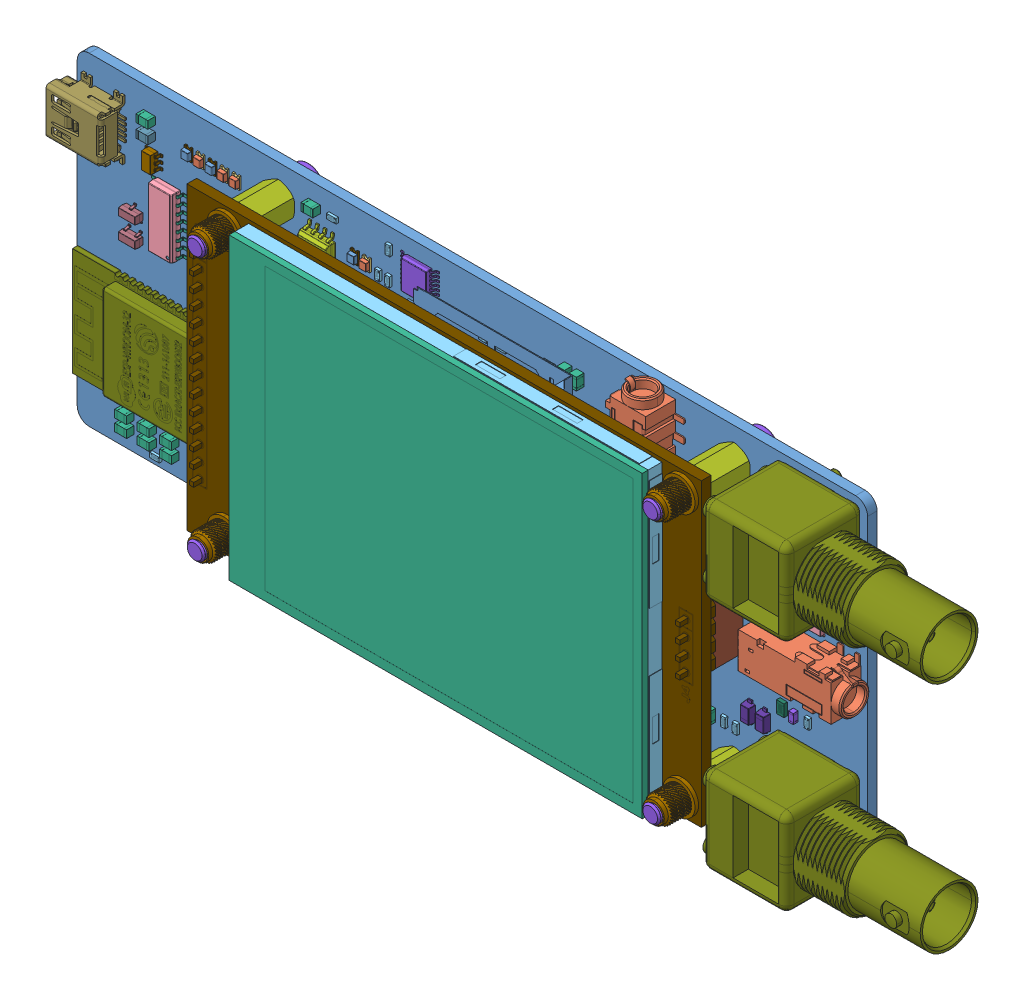
SolidWorks assembly TIK_PCB_20220619, configuration Default. Lengths in mm.
Overall size (153.42 59.57 22.01).
334 component instances, 49 part files, 0 mates.
Components (placement in the parent):
- TIK_PCB_20220619.step-1: TIK_PCB_20220619.step [Default] at origin size (153.42 59.57 22.01)
  - BoardTIK_PCB.step-1: BoardTIK_PCB.step [Default] at origin size (127 56 1.59)
    - Open CASCADE STEP translator 6.8 2.1.1.step-1: Open CASCADE STEP translator 6.8 2.1.1.step [Predeterminado] at (0 0 -1.59) size (127 56 1.59)
  - J6TIK_PCB.step-1: J6TIK_PCB.step [Default] at origin size (9 19.2 5.8)
    - CUI_DEVICES_SJ-43516-SMT-TR.step-1: CUI_DEVICES_SJ-43516-SMT-TR.step [Default] at (173.0501 135.9999 2.6) x (0 1 0) z (1 0 0) size (19.2 5.8 9)
  - U6TIK_PCB.step-1: U6TIK_PCB.step [Default] at origin size (4.9 3 1.1)
    - TI_VSSOP-8_DGK.step-1: TI_VSSOP-8_DGK.step [Default] at (178.0502 98.5 0) x (0 1 0) z (1 0 0) size (3 1.1 4.9)
  - U11TIK_PCB.step-1: U11TIK_PCB.step [Default] at origin size (2.9 2.8 1.1)
    - TI_-_TSOT-23-6_v2.step-1: TI_-_TSOT-23-6_v2.step [Default] at (199.75 115.5 0) x (0 -1 0) z (0 0 1) size (2.8 2.9 1.1)
  - R40TIK_PCB.step-1: R40TIK_PCB.step [Default] at origin size (0.8 1.6 0.45)
    - 0603_resistor.step-1: 0603_resistor.step [Default] at (177.1 122.3499 0) x (0 1 0) z (1 0 0) size (1.6 0.45 0.8)
  - R39TIK_PCB.step-1: R39TIK_PCB.step [Default] at origin size (1.6 0.8 0.45)
    - 0603_resistor.step-1: 0603_resistor.step [Default] at (189.4718 119.0829 0) x (1 0 0) z (0 -1 0) size (1.6 0.45 0.8)
  - C43TIK_PCB.step-1: C43TIK_PCB.step [Default] at origin size (1.27 2 1.27)
    - 0805_cap.step-1: 0805_cap.step [Default] at (196.363 115.3001 0.62) x (0 -1 0) z (0 0 1) size (2 1.27 1.27)
  - C42TIK_PCB.step-1: C42TIK_PCB.step [Default] at origin size (1.27 2 1.27)
    - 0805_cap.step-1: 0805_cap.step [Default] at (176.863 125.8001 0.62) x (0 -1 0) z (0 0 1) size (2 1.27 1.27)
  - C41TIK_PCB.step-1: C41TIK_PCB.step [Default] at origin size (2 1.27 1.27)
    - 0805_cap.step-1: 0805_cap.step [Default] at (189.1218 116.0459 0.62) x (1 0 0) z (0 0 1) size (2 1.27 1.27)
  - R20TIK_PCB.step-1: R20TIK_PCB.step [Default] at origin size (1.6 3.2 0.6)
    - 1206_resistor.step-1: 1206_resistor.step [Default] at (121.5499 105.1 0) x (0 -1 0) z (-1 0 0) size (3.2 0.6 1.6)
  - J5TIK_PCB.step-1: J5TIK_PCB.step [Default] at origin size (19.2 9 5.8)
    - CUI_DEVICES_SJ-43516-SMT-TR.step-1: CUI_DEVICES_SJ-43516-SMT-TR.step [Default] at (206.9999 109.9499 2.6) x (1 0 0) z (0 -1 0) size (19.2 5.8 9)
  - C25TIK_PCB.step-1: C25TIK_PCB.step [Default] at origin size (0.82 1.6 0.82)
    - 0603_cap.step-1: 0603_cap.step [Default] at (171.7501 98.5749 0) x (0 -1 0) z (-1 0 0) size (1.6 0.82 0.82)
  - R8TIK_PCB.step-1: R8TIK_PCB.step [Default] at origin size (1.6 0.8 0.45)
    - 0603_resistor.step-1: 0603_resistor.step [Default] at (118.8499 134.1 0) x (1 0 0) z (0 -1 0) size (1.6 0.45 0.8)
  - R2TIK_PCB.step-1: R2TIK_PCB.step [Default] at origin size (0.8 1.6 0.45)
    - 0603_resistor.step-1: 0603_resistor.step [Default] at (105.4 129.6501 0) x (0 -1 0) z (-1 0 0) size (1.6 0.45 0.8)
  - C33TIK_PCB.step-1: C33TIK_PCB.step [Default] at origin size (2 1.27 1.27)
    - 0805_cap.step-1: 0805_cap.step [Default] at (199.7501 119.387 0.62) x (-1 0 0) z (0 0 1) size (2 1.27 1.27)
  - C24TIK_PCB.step-1: C24TIK_PCB.step [Default] at origin size (1.6 3.2 1)
    - CAP_1206-1mm.step-1: CAP_1206-1mm.step [Default] at (191.0001 128.0499 0) x (0 -1 0) z (-1 0 0) size (3.2 1 1.6)
  - C23TIK_PCB.step-1: C23TIK_PCB.step [Default] at origin size (1.6 3.2 1)
    - CAP_1206-1mm.step-1: CAP_1206-1mm.step [Default] at (190.9999 91.9501 0) x (0 1 0) z (1 0 0) size (3.2 1 1.6)
  - U10TIK_PCB.step-1: U10TIK_PCB.step [Default] at origin size (10.01 6 1.75)
    - 6371753328.step-1: 6371753328.step [Default] at (149.545 124.325 0) x (0 1 0) z (0 0 1) size (6 10.01 1.75)
      - Body.step-1: Body.step [Default] at (-2 -5 0) size (4 10.01 1.65)
        - Open_CASCADE_STEP_translator_6.8_6.2.1.step-1: Open_CASCADE_STEP_translator_6.8_6.2.1.step [Default] at origin size (4 10.01 1.65)
      - Open_CASCADE_STEP_translator_6.8_6.1.step-1: Open_CASCADE_STEP_translator_6.8_6.1.step [Default] at (-2 -5 0.001) size (0.5 0.5 0)
      - Leader.step-1: Leader.step [Default] at (-2 -4.445 0) x (-1 0 0) z (0 0 1) size (1 0.41 0.97)
      - Leader.step-2: Leader.step [Default] at (-2 -3.175 0) x (-1 0 0) z (0 0 1) size (1 0.41 0.97)
      - Leader.step-3: Leader.step [Default] at (-2 -1.905 0) x (-1 0 0) z (0 0 1) size (1 0.41 0.97)
      - Leader.step-4: Leader.step [Default] at (-2 -0.635 0) x (-1 0 0) z (0 0 1) size (1 0.41 0.97)
      - Leader.step-5: Leader.step [Default] at (-2 0.635 0) x (-1 0 0) z (0 0 1) size (1 0.41 0.97)
      - Leader.step-6: Leader.step [Default] at (-2 1.905 0) x (-1 0 0) z (0 0 1) size (1 0.41 0.97)
      - Leader.step-7: Leader.step [Default] at (-2 3.175 0) x (-1 0 0) z (0 0 1) size (1 0.41 0.97)
      - Leader.step-8: Leader.step [Default] at (-2 4.445 0) x (-1 0 0) z (0 0 1) size (1 0.41 0.97)
      - Leader.step-9: Leader.step [Default] at (2 -4.445 0) size (1 0.41 0.97)
      - Leader.step-10: Leader.step [Default] at (2 -3.175 0) size (1 0.41 0.97)
      - Leader.step-11: Leader.step [Default] at (2 -1.905 0) size (1 0.41 0.97)
      - Leader.step-12: Leader.step [Default] at (2 -0.635 0) size (1 0.41 0.97)
      - Leader.step-13: Leader.step [Default] at (2 0.635 0) size (1 0.41 0.97)
      - Leader.step-14: Leader.step [Default] at (2 1.905 0) size (1 0.41 0.97)
      - Leader.step-15: Leader.step [Default] at (2 3.175 0) size (1 0.41 0.97)
      - Leader.step-16: Leader.step [Default] at (2 4.445 0) size (1 0.41 0.97)
  - R34TIK_PCB.step-1: R34TIK_PCB.step [Default] at origin size (0.8 1.6 0.45)
    - 0603_resistor.step-1: 0603_resistor.step [Default] at (156.1 119.3499 0) x (0 1 0) z (1 0 0) size (1.6 0.45 0.8)
  - R33TIK_PCB.step-1: R33TIK_PCB.step [Default] at origin size (0.8 1.6 0.45)
    - 0603_resistor.step-1: 0603_resistor.step [Default] at (156.9 126.1001 0) x (0 -1 0) z (-1 0 0) size (1.6 0.45 0.8)
  - R38TIK_PCB.step-1: R38TIK_PCB.step [Default] at origin size (1.6 0.8 0.45)
    - 0603_resistor.step-1: 0603_resistor.step [Default] at (150.5001 118.85 0) x (-1 0 0) z (0 1 0) size (1.6 0.45 0.8)
  - R37TIK_PCB.step-1: R37TIK_PCB.step [Default] at origin size (1.6 0.8 0.45)
    - 0603_resistor.step-1: 0603_resistor.step [Default] at (147.1501 128.65 0) x (-1 0 0) z (0 1 0) size (1.6 0.45 0.8)
  - R36TIK_PCB.step-1: R36TIK_PCB.step [Default] at origin size (1.6 0.8 0.45)
    - 0603_resistor.step-1: 0603_resistor.step [Default] at (147.5001 118.85 0) x (-1 0 0) z (0 1 0) size (1.6 0.45 0.8)
  - R35TIK_PCB.step-1: R35TIK_PCB.step [Default] at origin size (1.6 0.8 0.45)
    - 0603_resistor.step-1: 0603_resistor.step [Default] at (144.2501 128.6 0) x (-1 0 0) z (0 1 0) size (1.6 0.45 0.8)
  - Q6TIK_PCB.step-1: Q6TIK_PCB.step [Default] at origin size (2.9 2.32 1.5)
    - sot-23-3-nxp.step-1: sot-23-3-nxp.step [Default] at (142.25 119.2501 0) x (-1 0 0) z (0 1 0) size (2.9 1.5 2.32)
  - FB2TIK_PCB.step-1: FB2TIK_PCB.step [Default] at origin size (2 1.27 1.27)
    - FER_0805.step-1: FER_0805.step [Default] at (154.9501 130.887 0.62) x (-1 0 0) z (0 0 1) size (2 1.27 1.27)
  - C36TIK_PCB.step-1: C36TIK_PCB.step [Default] at origin size (1.27 2 1.27)
    - 0805_cap.step-1: 0805_cap.step [Default] at (143.837 126.2499 0.62) x (0 1 0) z (0 0 1) size (2 1.27 1.27)
  - C35TIK_PCB.step-1: C35TIK_PCB.step [Default] at origin size (1.27 2 1.27)
    - 0805_cap.step-1: 0805_cap.step [Default] at (141.837 126.2499 0.62) x (0 1 0) z (0 0 1) size (2 1.27 1.27)
  - C34TIK_PCB.step-1: C34TIK_PCB.step [Default] at origin size (1.27 2 1.27)
    - 0805_cap.step-1: 0805_cap.step [Default] at (139.837 126.2499 0.62) x (0 1 0) z (0 0 1) size (2 1.27 1.27)
  - C39TIK_PCB.step-1: C39TIK_PCB.step [Default] at origin size (1.27 2 1.27)
    - 0805_cap.step-1: 0805_cap.step [Default] at (157.137 122.6999 0.62) x (0 1 0) z (0 0 1) size (2 1.27 1.27)
  - C40TIK_PCB.step-1: C40TIK_PCB.step [Default] at origin size (2 1.27 1.27)
    - 0805_cap.step-1: 0805_cap.step [Default] at (153.8001 119.637 0.62) x (-1 0 0) z (0 0 1) size (2 1.27 1.27)
  - C38TIK_PCB.step-1: C38TIK_PCB.step [Default] at origin size (1.27 2 1.27)
    - 0805_cap.step-1: 0805_cap.step [Default] at (157.3629 131.0501 0.62) x (0 -1 0) z (0 0 1) size (2 1.27 1.27)
  - C37TIK_PCB.step-1: C37TIK_PCB.step [Default] at origin size (1.27 2 1.27)
    - 0805_cap.step-1: 0805_cap.step [Default] at (159.363 131.0501 0.62) x (0 -1 0) z (0 0 1) size (2 1.27 1.27)
  - R11TIK_PCB.step-1: R11TIK_PCB.step [Default] at origin size (1.6 0.8 0.45)
    - 0603_resistor.step-1: 0603_resistor.step [Default] at (144.7501 90.6 0) x (-1 0 0) z (0 1 0) size (1.6 0.45 0.8)
  - C26TIK_PCB.step-1: C26TIK_PCB.step [Default] at origin size (1.27 2 1.27)
    - 0805_cap.step-1: 0805_cap.step [Default] at (169.113 98.2001 0.62) x (0 -1 0) z (0 0 1) size (2 1.27 1.27)
  - R17TIK_PCB.step-1: R17TIK_PCB.step [Default] at origin size (1.25 2 0.6)
    - 0805_resistor.step-1: 0805_resistor.step [Default] at (174.375 98.625 0) x (0 -1 0) z (-1 0 0) size (2 0.6 1.25)
  - R16TIK_PCB.step-1: R16TIK_PCB.step [Default] at origin size (0.8 1.6 0.45)
    - 0603_resistor.step-1: 0603_resistor.step [Default] at (186.65 123.6001 0) x (0 -1 0) z (-1 0 0) size (1.6 0.45 0.8)
  - R15TIK_PCB.step-1: R15TIK_PCB.step [Default] at origin size (0.8 1.6 0.45)
    - 0603_resistor.step-1: 0603_resistor.step [Default] at (197.85 100.3749 0) x (0 1 0) z (1 0 0) size (1.6 0.45 0.8)
  - R14TIK_PCB.step-1: R14TIK_PCB.step [Default] at origin size (1.25 2 0.6)
    - 0805_resistor.step-1: 0805_resistor.step [Default] at (194.625 100.475 0) x (0 -1 0) z (-1 0 0) size (2 0.6 1.25)
  - J3TIK_PCB.step-1: J3TIK_PCB.step [Default] at origin size (35.41 14.41 17.87)
    - 31-71043_1.step-1: 31-71043_1.step [Default] at (202.8647 129.4999 6.6) x (1 0 0) z (0 -1 0) size (35.41 17.87 14.41)
  - J2TIK_PCB.step-1: J2TIK_PCB.step [Default] at origin size (35.41 14.41 17.87)
    - 31-71043_1.step-1: 31-71043_1.step [Default] at (202.8647 90.4999 6.6) x (1 0 0) z (0 -1 0) size (35.41 17.87 14.41)
  - D5TIK_PCB.step-1: D5TIK_PCB.step [Default] at origin size (1.6 3.5 1.1)
    - SOD123F.step-1: SOD123F.step [Default] at (191.0001 122.8199 0) x (0 -1 0) z (-1 0 0) size (3.5 1.1 1.6)
  - D4TIK_PCB.step-1: D4TIK_PCB.step [Default] at origin size (1.6 3.5 1.1)
    - SOD123F.step-1: SOD123F.step [Default] at (188.4999 122.8201 0) x (0 1 0) z (1 0 0) size (3.5 1.1 1.6)
  - D3TIK_PCB.step-1: D3TIK_PCB.step [Default] at origin size (1.6 3.5 1.1)
    - SOD123F.step-1: SOD123F.step [Default] at (190.9999 97.0701 0) x (0 1 0) z (1 0 0) size (3.5 1.1 1.6)
  - D2TIK_PCB.step-1: D2TIK_PCB.step [Default] at origin size (1.6 3.5 1.1)
    - SOD123F.step-1: SOD123F.step [Default] at (188.5001 97.0699 0) x (0 -1 0) z (-1 0 0) size (3.5 1.1 1.6)
  - C27TIK_PCB.step-1: C27TIK_PCB.step [Default] at origin size (1.27 2 1.27)
    - 0805_cap.step-1: 0805_cap.step [Default] at (166.863 98.2001 0.62) x (0 -1 0) z (0 0 1) size (2 1.27 1.27)
  - C22TIK_PCB.step-1: C22TIK_PCB.step [Default] at origin size (0.82 1.6 0.82)
    - 0603_cap.step-1: 0603_cap.step [Default] at (196.0001 100.2749 0) x (0 -1 0) z (-1 0 0) size (1.6 0.82 0.82)
  - R29TIK_PCB.step-1: R29TIK_PCB.step [Default] at origin size (0.8 1.6 0.45)
    - 0603_resistor.step-1: 0603_resistor.step [Default] at (100.4 124.1001 0) x (0 -1 0) z (-1 0 0) size (1.6 0.45 0.8)
  - D11TIK_PCB.step-1: D11TIK_PCB.step [Default] at origin size (1.25 2 0.9)
    - LED_0805_Base_RED.step-1: LED_0805_Base_RED.step [Default] at (98.75 130.9501 0) x (0 1 0) z (1 0 0) size (2 0.4 1.25)
    - LED_0805_Lens_RED.step-1: LED_0805_Lens_RED.step [Default] at (98.75 130.9501 0) x (0 1 0) z (1 0 0) size (1.3 0.6 1.25)
  - D10TIK_PCB.step-1: D10TIK_PCB.step [Default] at origin size (1.25 2 0.9)
    - LED_0805_Lens_GREEN.step-1: LED_0805_Lens_GREEN.step [Default] at (100.75 130.9501 0) x (0 1 0) z (1 0 0) size (1.3 0.6 1.25)
    - LED_0805_Base_GREEN.step-1: LED_0805_Base_GREEN.step [Default] at (100.75 130.9501 0) x (0 1 0) z (1 0 0) size (2 0.4 1.25)
  - D9TIK_PCB.step-1: D9TIK_PCB.step [Default] at origin size (1.25 2 0.9)
    - LED_0805_Lens_RED.step-1: LED_0805_Lens_RED.step [Default] at (94.75 130.9501 0) x (0 1 0) z (1 0 0) size (1.3 0.6 1.25)
    - LED_0805_Base_RED.step-1: LED_0805_Base_RED.step [Default] at (94.75 130.9501 0) x (0 1 0) z (1 0 0) size (2 0.4 1.25)
  - D1TIK_PCB.step-1: D1TIK_PCB.step [Default] at origin size (1.25 2 0.9)
    - LED_0805_Base_GREEN.step-1: LED_0805_Base_GREEN.step [Default] at (102.75 130.9501 0) x (0 1 0) z (1 0 0) size (2 0.4 1.25)
    - LED_0805_Lens_GREEN.step-1: LED_0805_Lens_GREEN.step [Default] at (102.75 130.9501 0) x (0 1 0) z (1 0 0) size (1.3 0.6 1.25)
  - D6TIK_PCB.step-1: D6TIK_PCB.step [Default] at origin size (1.25 2 0.9)
    - LED_0805_Lens_GREEN.step-1: LED_0805_Lens_GREEN.step [Default] at (124.5 129.8999 0) x (0 -1 0) z (-1 0 0) size (1.3 0.6 1.25)
    - LED_0805_Base_GREEN.step-1: LED_0805_Base_GREEN.step [Default] at (124.5 129.8999 0) x (0 -1 0) z (-1 0 0) size (2 0.4 1.25)
  - D7TIK_PCB.step-1: D7TIK_PCB.step [Default] at origin size (1.25 2 0.9)
    - LED_0805_Base_RED.step-1: LED_0805_Base_RED.step [Default] at (122.5 129.8999 0) x (0 -1 0) z (-1 0 0) size (2 0.4 1.25)
    - LED_0805_Lens_RED.step-1: LED_0805_Lens_RED.step [Default] at (122.5 129.8999 0) x (0 -1 0) z (-1 0 0) size (1.3 0.6 1.25)
  - D8TIK_PCB.step-1: D8TIK_PCB.step [Default] at origin size (1.25 2 0.9)
    - LED_0805_Base_GREEN.step-1: LED_0805_Base_GREEN.step [Default] at (96.75 130.9501 0) x (0 1 0) z (1 0 0) size (2 0.4 1.25)
    - LED_0805_Lens_GREEN.step-1: LED_0805_Lens_GREEN.step [Default] at (96.75 130.9501 0) x (0 1 0) z (1 0 0) size (1.3 0.6 1.25)
  - R24TIK_PCB.step-1: R24TIK_PCB.step [Default] at origin size (0.8 1.6 0.45)
    - 0603_resistor.step-1: 0603_resistor.step [Default] at (128.6 129.3501 0) x (0 -1 0) z (-1 0 0) size (1.6 0.45 0.8)
  - C29TIK_PCB.step-1: C29TIK_PCB.step [Default] at origin size (2 1.27 1.27)
    - 0805_cap.step-1: 0805_cap.step [Default] at (116.5501 118.387 0.62) x (-1 0 0) z (0 0 1) size (2 1.27 1.27)
  - U9TIK_PCB.step-1: U9TIK_PCB.step [Default] at origin size (6 10.01 1.75)
    - 6371753168.step-1: 6371753168.step [Default] at (91.5 120 0) x (-1 0 0) z (0 0 1) size (6 10.01 1.75)
      - Body-1.step-1: Body-1.step [Default] at (-2 -5 0) size (4 10.01 1.65)
        - Open_CASCADE_STEP_translator_6.8_6.2.1-0.step-1: Open_CASCADE_STEP_translator_6.8_6.2.1-0.step [Default] at origin size (4 10.01 1.65)
      - Open_CASCADE_STEP_translator_6.8_6.1-1.step-1: Open_CASCADE_STEP_translator_6.8_6.1-1.step [Default] at (-2 -5 0.001) size (0.5 0.5 0)
      - Leader-2.step-1: Leader-2.step [Default] at (-2 -4.445 0) x (-1 0 0) z (0 0 1) size (1 0.41 0.97)
      - Leader-2.step-2: Leader-2.step [Default] at (-2 -3.175 0) x (-1 0 0) z (0 0 1) size (1 0.41 0.97)
      - Leader-2.step-3: Leader-2.step [Default] at (-2 -1.905 0) x (-1 0 0) z (0 0 1) size (1 0.41 0.97)
      - Leader-2.step-4: Leader-2.step [Default] at (-2 -0.635 0) x (-1 0 0) z (0 0 1) size (1 0.41 0.97)
      - Leader-2.step-5: Leader-2.step [Default] at (-2 0.635 0) x (-1 0 0) z (0 0 1) size (1 0.41 0.97)
      - Leader-2.step-6: Leader-2.step [Default] at (-2 1.905 0) x (-1 0 0) z (0 0 1) size (1 0.41 0.97)
      - Leader-2.step-7: Leader-2.step [Default] at (-2 3.175 0) x (-1 0 0) z (0 0 1) size (1 0.41 0.97)
      - Leader-2.step-8: Leader-2.step [Default] at (-2 4.445 0) x (-1 0 0) z (0 0 1) size (1 0.41 0.97)
      - Leader-2.step-9: Leader-2.step [Default] at (2 -4.445 0) size (1 0.41 0.97)
      - Leader-2.step-10: Leader-2.step [Default] at (2 -3.175 0) size (1 0.41 0.97)
      - Leader-2.step-11: Leader-2.step [Default] at (2 -1.905 0) size (1 0.41 0.97)
      - Leader-2.step-12: Leader-2.step [Default] at (2 -0.635 0) size (1 0.41 0.97)
      - Leader-2.step-13: Leader-2.step [Default] at (2 0.635 0) size (1 0.41 0.97)
      - Leader-2.step-14: Leader-2.step [Default] at (2 1.905 0) size (1 0.41 0.97)
      - Leader-2.step-15: Leader-2.step [Default] at (2 3.175 0) size (1 0.41 0.97)
      - Leader-2.step-16: Leader-2.step [Default] at (2 4.445 0) size (1 0.41 0.97)
  - U8TIK_PCB.step-1: U8TIK_PCB.step [Default] at origin size (4.91 6 1.75)
    - TI_-_SOIC-8_-_D008A_v3.step-1: TI_-_SOIC-8_-_D008A_v3.step [Default] at (116.635 104.1 0) x (0 -1 0) z (0 0 1) size (6 4.9 1.75)
  - U7TIK_PCB.step-1: U7TIK_PCB.step [Default] at origin size (6.4 5 1.2)
    - TI_-_SOP-16_-_PWP0016C_v2.step-1: TI_-_SOP-16_-_PWP0016C_v2.step [Default] at (133.35 132.225 0) x (-1 0 0) z (0 0 1) size (6.4 5 1.2)
      - Component4.step-1: Component4.step [Default] at origin size (6.4 5 1.2)
  - U4TIK_PCB.step-1: U4TIK_PCB.step [Default] at origin size (4.91 6 1.75)
    - TI_-_SOIC-8_-_D008A_v3.step-1: TI_-_SOIC-8_-_D008A_v3.step [Default] at (116.885 128.5 0) x (0 1 0) z (0 0 1) size (6 4.9 1.75)
  - U3TIK_PCB.step-1: U3TIK_PCB.step [Default] at origin size (2.82 2.9 1.45)
    - sot-23-6-atmel.step-1: sot-23-6-atmel.step [Default] at (117.875 122.5499 0) x (0 -1 0) z (-1 0 0) size (2.9 1.45 2.82)
  - U2TIK_PCB.step-1: U2TIK_PCB.step [Default] at origin size (1.85 2 1.1)
    - sc_82ab.step-1: sc_82ab.step [Default] at (173.7746 94.1652 0) x (0 -1 0) z (0 0 -1) size (2 1.85 1.1)
  - U1TIK_PCB.step-1: U1TIK_PCB.step [Default] at origin size (3.1 3 1.45)
    - DIODES_INC_-_SOT-23-5_-_N.step-1: DIODES_INC_-_SOT-23-5_-_N.step [Default] at (126.5 105.2501 0) x (0 1 0) z (0 0 1) size (3 3.1 1.45)
  - S4TIK_PCB.step-1: S4TIK_PCB.step [Default] at origin size (8 3.61 2.52)
    - Tactile_Switch_SMD_6x3.6mm_H=2.5mm_RS-282G05A3-SM_RT.step-1: Tactile_Switch_SMD_6x3.6mm_H=2.5mm_RS-282G05A3-SM_RT.step [Default] at (99.1232 87.0004 0) x (-1 0 0) z (0 0 1) size (8 3.6 2.52)
  - S1TIK_PCB.step-1: S1TIK_PCB.step [Default] at origin size (17.45 11.87 3.02)
    - SLLB510100_SCALED_CROP.step-1: SLLB510100_SCALED_CROP.step [Default] at (150.023 87.4461 7.7) x (1 0 0) z (0 0 1) size (17.45 11.87 3.02)
  - S3TIK_PCB.step-1: S3TIK_PCB.step [Default] at origin size (8 3.61 2.52)
    - Tactile_Switch_SMD_6x3.6mm_H=2.5mm_RS-282G05A3-SM_RT.step-1: Tactile_Switch_SMD_6x3.6mm_H=2.5mm_RS-282G05A3-SM_RT.step [Default] at (164.0163 87.0004 0) x (-1 0 0) z (0 0 1) size (8 3.6 2.52)
  - S2TIK_PCB.step-1: S2TIK_PCB.step [Default] at origin size (8 3.61 2.52)
    - Tactile_Switch_SMD_6x3.6mm_H=2.5mm_RS-282G05A3-SM_RT.step-1: Tactile_Switch_SMD_6x3.6mm_H=2.5mm_RS-282G05A3-SM_RT.step [Default] at (177.5163 87.0004 0) x (-1 0 0) z (0 0 1) size (8 3.6 2.52)
  - R32TIK_PCB.step-1: R32TIK_PCB.step [Default] at origin size (1.6 0.8 0.45)
    - 0603_resistor.step-1: 0603_resistor.step [Default] at (115.6399 86.65 0) x (1 0 0) z (0 -1 0) size (1.6 0.45 0.8)
  - R31TIK_PCB.step-1: R31TIK_PCB.step [Default] at origin size (1.6 0.8 0.45)
    - 0603_resistor.step-1: 0603_resistor.step [Default] at (115.6399 88.4 0) x (1 0 0) z (0 -1 0) size (1.6 0.45 0.8)
  - R30TIK_PCB.step-1: R30TIK_PCB.step [Default] at origin size (1.6 0.8 0.45)
    - 0603_resistor.step-1: 0603_resistor.step [Default] at (118.3499 98.3 0) x (1 0 0) z (0 -1 0) size (1.6 0.45 0.8)
  - R28TIK_PCB.step-1: R28TIK_PCB.step [Default] at origin size (0.8 1.6 0.45)
    - 0603_resistor.step-1: 0603_resistor.step [Default] at (102.15 124.1001 0) x (0 -1 0) z (-1 0 0) size (1.6 0.45 0.8)
  - R27TIK_PCB.step-1: R27TIK_PCB.step [Default] at origin size (0.8 1.6 0.45)
    - 0603_resistor.step-1: 0603_resistor.step [Default] at (96.9 124.1001 0) x (0 -1 0) z (-1 0 0) size (1.6 0.45 0.8)
  - R19TIK_PCB.step-1: R19TIK_PCB.step [Default] at origin size (1.6 0.8 0.45)
    - 0603_resistor.step-1: 0603_resistor.step [Default] at (133.9499 129 0) x (1 0 0) z (0 -1 0) size (1.6 0.45 0.8)
  - R18TIK_PCB.step-1: R18TIK_PCB.step [Default] at origin size (0.8 1.6 0.45)
    - 0603_resistor.step-1: 0603_resistor.step [Default] at (128.65 133.8501 0) x (0 -1 0) z (-1 0 0) size (1.6 0.45 0.8)
  - R25TIK_PCB.step-1: R25TIK_PCB.step [Default] at origin size (0.8 1.6 0.45)
    - 0603_resistor.step-1: 0603_resistor.step [Default] at (123 114.5499 0) x (0 1 0) z (1 0 0) size (1.6 0.45 0.8)
  - R26TIK_PCB.step-1: R26TIK_PCB.step [Default] at origin size (0.8 1.6 0.45)
    - 0603_resistor.step-1: 0603_resistor.step [Default] at (98.65 124.1001 0) x (0 -1 0) z (-1 0 0) size (1.6 0.45 0.8)
  - R13TIK_PCB.step-1: R13TIK_PCB.step [Default] at origin size (1.6 0.8 0.45)
    - 0603_resistor.step-1: 0603_resistor.step [Default] at (162.2501 89.6 0) x (-1 0 0) z (0 1 0) size (1.6 0.45 0.8)
  - R12TIK_PCB.step-1: R12TIK_PCB.step [Default] at origin size (1.6 0.8 0.45)
    - 0603_resistor.step-1: 0603_resistor.step [Default] at (89.3501 84 0) x (-1 0 0) z (0 1 0) size (1.6 0.45 0.8)
  - R10TIK_PCB.step-1: R10TIK_PCB.step [Default] at origin size (1.6 0.8 0.45)
    - 0603_resistor.step-1: 0603_resistor.step [Default] at (157.9999 91.4 0) x (1 0 0) z (0 -1 0) size (1.6 0.45 0.8)
  - R9TIK_PCB.step-1: R9TIK_PCB.step [Default] at origin size (1.6 0.8 0.45)
    - 0603_resistor.step-1: 0603_resistor.step [Default] at (155.1499 91.4 0) x (1 0 0) z (0 -1 0) size (1.6 0.45 0.8)
  - R23TIK_PCB.step-1: R23TIK_PCB.step [Default] at origin size (0.8 1.6 0.45)
    - 0603_resistor.step-1: 0603_resistor.step [Default] at (126.9 129.3501 0) x (0 -1 0) z (-1 0 0) size (1.6 0.45 0.8)
  - R7TIK_PCB.step-1: R7TIK_PCB.step [Default] at origin size (0.8 1.6 0.45)
    - 0603_resistor.step-1: 0603_resistor.step [Default] at (121.15 125.4001 0) x (0 -1 0) z (-1 0 0) size (1.6 0.45 0.8)
  - R6TIK_PCB.step-1: R6TIK_PCB.step [Default] at origin size (0.8 1.6 0.45)
    - 0603_resistor.step-1: 0603_resistor.step [Default] at (114.15 118.3501 0) x (0 -1 0) z (-1 0 0) size (1.6 0.45 0.8)
  - R5TIK_PCB.step-1: R5TIK_PCB.step [Default] at origin size (0.8 1.6 0.45)
    - 0603_resistor.step-1: 0603_resistor.step [Default] at (184.65 93.6001 0) x (0 -1 0) z (-1 0 0) size (1.6 0.45 0.8)
  - R4TIK_PCB.step-1: R4TIK_PCB.step [Default] at origin size (0.8 1.6 0.45)
    - 0603_resistor.step-1: 0603_resistor.step [Default] at (186.6374 93.6253 0) x (0 -1 0) z (-1 0 0) size (1.6 0.45 0.8)
  - R3TIK_PCB.step-1: R3TIK_PCB.step [Default] at origin size (1.25 2 0.6)
    - 0805_resistor.step-1: 0805_resistor.step [Default] at (121.875 94.8 0) x (0 1 0) z (1 0 0) size (2 0.6 1.25)
  - R1TIK_PCB.step-1: R1TIK_PCB.step [Default] at origin size (2 1.25 0.6)
    - 0805_resistor.step-1: 0805_resistor.step [Default] at (123.3 101.925 0) x (1 0 0) z (0 -1 0) size (2 0.6 1.25)
  - R22TIK_PCB.step-1: R22TIK_PCB.step [Default] at origin size (1.6 0.8 0.45)
    - 0603_resistor.step-1: 0603_resistor.step [Default] at (115.3001 97.5 0) x (-1 0 0) z (0 1 0) size (1.6 0.45 0.8)
  - R21TIK_PCB.step-1: R21TIK_PCB.step [Default] at origin size (1.6 0.8 0.45)
    - 0603_resistor.step-1: 0603_resistor.step [Default] at (115.3001 99.1 0) x (-1 0 0) z (0 1 0) size (1.6 0.45 0.8)
  - Q5TIK_PCB.step-1: Q5TIK_PCB.step [Default] at origin size (2.9 2.32 1.5)
    - sot-23-3-nxp.step-1: sot-23-3-nxp.step [Default] at (119.2499 95.4999 0) x (1 0 0) z (0 -1 0) size (2.9 1.5 2.32)
  - Q4TIK_PCB.step-1: Q4TIK_PCB.step [Default] at origin size (2.9 2.32 1.5)
    - sot-23-3-nxp.step-1: sot-23-3-nxp.step [Default] at (85.75 114.5001 0) x (-1 0 0) z (0 1 0) size (2.9 1.5 2.32)
  - Q3TIK_PCB.step-1: Q3TIK_PCB.step [Default] at origin size (2.9 2.32 1.5)
    - sot-23-3-nxp.step-1: sot-23-3-nxp.step [Default] at (85.7499 117.9999 0) x (1 0 0) z (0 -1 0) size (2.9 1.5 2.32)
  - Q2TIK_PCB.step-1: Q2TIK_PCB.step [Default] at origin size (6.73 10.1 2.4)
    - User_Library-DPAK_TO-252AA.step-1: User_Library-DPAK_TO-252AA.step [Default] at (130.5499 117.4999 0) x (-1 0 0) z (0 1 0) size (6.73 2.4 10.1)
  - Q1TIK_PCB.step-1: Q1TIK_PCB.step [Default] at origin size (3 6.42 1.2)
    - TSSOP-8.step-1: TSSOP-8.step [Default] at (123.3251 121.5499 0) x (-1 0 0) z (0 1 0) size (3 1.2 6.42)
  - MCU1TIK_PCB.step-1: MCU1TIK_PCB.step [Default] at origin size (25.5 18 2.91)
    - User_Library-ESP321.step-1: User_Library-ESP321.step [Default] at (88.8419 99.2234 0) x (0 1 0) z (0 0 1) size (18 25.5 2.91)
  - L1TIK_PCB.step-1: L1TIK_PCB.step [Default] at origin size (4 4 1.8)
    - NR4018.step-1: NR4018.step [Default] at (127.4507 99.7473 0) x (-1 0 0) z (0 0 1) size (4 4 1.8)
  - J4TIK_PCB.step-1: J4TIK_PCB.step [Default] at origin size (85.9 50.19 19)
    - 2.8_TFT_Module_mod.step-1: 2.8_TFT_Module_mod.step [Default] at (146.1 110.01 7.2) x (0 1 0) z (0 0 1) size (50.19 85.9 12.99)
      - 2.8_TFT_Module.stp.step-1: 2.8_TFT_Module.stp.step [Default] at origin size (50.19 85.9 11.99)
        - 2.8_LCD_TFT_Module_-_Without_Glass.stp.step-1: 2.8_LCD_TFT_Module_-_Without_Glass.stp.step [Default] at origin size (50.14 85.9 10.67)
        - 5035000993.stp.step-1: 5035000993.stp.step [Default] at (3.5564 -3.3047 -2.85) x (0 1 0) z (0 0 -1) size (28.6 21.52 2.95)
        - 0603_Resistor.stp.step-1: 0603_Resistor.stp.step [Default] at (-2.2311 -3.165 0.0025) x (-1 0 0) z (0 0 -1) size (1.6 0.85 0.47)
        - 0603_Capacitor.stp.step-1: 0603_Capacitor.stp.step [Default] at (-14.5217 25.6289 0.0025) x (1 0 0) z (0 0 -1) size (1.6 0.84 0.84)
        - 0603_Capacitor.stp.step-2: 0603_Capacitor.stp.step [Default] at (-2.484 19.738 0.0025) x (-1 0 0) z (0 0 -1) size (1.6 0.84 0.84)
        - 0603_Resistor.stp.step-2: 0603_Resistor.stp.step [Default] at (-3.8795 -4.7617 0.0025) x (1 0 0) z (0 0 -1) size (1.6 0.85 0.47)
        - 0603_Resistor.stp.step-3: 0603_Resistor.stp.step [Default] at (-2.3355 -0.9936 0.0025) x (-1 0 0) z (0 0 -1) size (1.6 0.85 0.47)
        - 0603_Resistor.stp.step-4: 0603_Resistor.stp.step [Default] at (-12.9341 26.6747 0.0025) x (-1 0 0) z (0 0 -1) size (1.6 0.85 0.47)
        - 0603_Resistor.stp.step-5: 0603_Resistor.stp.step [Default] at (4.5338 19.5922 0.0025) x (-1 0 0) z (0 0 -1) size (1.6 0.85 0.47)
        - 0603_Resistor.stp.step-6: 0603_Resistor.stp.step [Default] at (4.3803 26.5372 0.0025) x (-1 0 0) z (0 0 -1) size (1.6 0.85 0.47)
        - SOT23-3.stp.step-1: SOT23-3.stp.step [Default] at (3.6167 23.9432 0.105) x (0.003406 0.999994 0) z (0 0 -1) size (2.84 3 1.19)
        - SOT23-3.stp.step-2: SOT23-3.stp.step [Default] at (-3.3735 23.944 0.105) x (0.999985 -0.005499 0) z (0 0 -1) size (2.84 3 1.19)
        - 2.8in_TFT(Without_Glass)-_Tucked_Cable.stp.step-1: 2.8in_TFT(Without_Glass)-_Tucked_Cable.stp.step [Default] at (-0.0571 -2.2987 1.6256) x (-1 0 0) z (0 0 1) size (50.11 69.48 2.74)
      - GLASS.step-1: GLASS.step [Default] at (24.922 -36.8028 4.3434) x (-1 0 0) z (0 1 0) size (49.96 1 69.01)
    - spacer_m3_7cm.step-1: spacer_m3_7cm.step [Default] at (109.9199 132 0.1) x (0 1 0) z (1 0 0) size (5.77 7.3 5)
    - ISO_4762_M3_x_16_-_16S.step-1: ISO_4762_M3_x_16_-_16S.step [Default] at (109.9199 132.0001 -4.7) x (0 0 1) z (1 0 0) size (19 5.5 5.5)
    - F2-B-M3-Pressfit_3.step-1: F2-B-M3-Pressfit_3.step [Default] at (109.92 132.0001 11.8) x (0 1 0) z (-1 0 0) size (5.4 4.81 5.4)
    - spacer_m3_7cm.step-2: spacer_m3_7cm.step [Default] at (185.9999 88.0001 0.1) x (0 1 0) z (1 0 0) size (5.77 7.3 5)
    - ISO_4762_M3_x_16_-_16S.step-2: ISO_4762_M3_x_16_-_16S.step [Default] at (185.9999 88.0001 -4.7) x (0 0 1) z (1 0 0) size (19 5.5 5.5)
    - F2-B-M3-Pressfit_3.step-2: F2-B-M3-Pressfit_3.step [Default] at (186 88.0001 11.8) x (0 1 0) z (-1 0 0) size (5.4 4.81 5.4)
    - spacer_m3_7cm.step-3: spacer_m3_7cm.step [Default] at (185.9999 132 0.1) x (0 1 0) z (1 0 0) size (5.77 7.3 5)
    - ISO_4762_M3_x_16_-_16S.step-3: ISO_4762_M3_x_16_-_16S.step [Default] at (185.9999 132.0001 -4.7) x (0 0 1) z (1 0 0) size (19 5.5 5.5)
    - F2-B-M3-Pressfit_3.step-3: F2-B-M3-Pressfit_3.step [Default] at (186 132.0001 11.8) x (0 1 0) z (-1 0 0) size (5.4 4.81 5.4)
    - spacer_m3_7cm.step-4: spacer_m3_7cm.step [Default] at (109.9199 88.0001 0.1) x (0 1 0) z (1 0 0) size (5.77 7.3 5)
    - ROW_HEADER_low_5mm_1X14PIN.step-1: ROW_HEADER_low_5mm_1X14PIN.step [Default] at (104.9951 93.5049 0.05) x (0 1 0) z (1 0 0) size (35.56 7 2.54)
    - ROW_HEADER_low_5mm_1X4PIN.step-1: ROW_HEADER_low_5mm_1X4PIN.step [Default] at (185.9951 106.1999 0.05) x (0 1 0) z (1 0 0) size (10.16 7 2.54)
    - ISO_4762_M3_x_16_-_16S.step-4: ISO_4762_M3_x_16_-_16S.step [Default] at (109.9199 88.0001 -4.7) x (0 0 1) z (1 0 0) size (19 5.5 5.5)
    - F2-B-M3-Pressfit_3.step-4: F2-B-M3-Pressfit_3.step [Default] at (109.92 88.0001 11.8) x (0 1 0) z (-1 0 0) size (5.4 4.81 5.4)
  - D13TIK_PCB.step-1: D13TIK_PCB.step [Default] at origin size (3.5 1.6 1.1)
    - SOD123F.step-1: SOD123F.step [Default] at (119.5699 86.4999 0) x (-1 0 0) z (0 1 0) size (3.5 1.1 1.6)
  - D12TIK_PCB.step-1: D12TIK_PCB.step [Default] at origin size (3.5 1.6 1.1)
    - SOD123F.step-1: SOD123F.step [Default] at (119.5701 88.7501 0) x (1 0 0) z (0 -1 0) size (3.5 1.1 1.6)
  - C32TIK_PCB.step-1: C32TIK_PCB.step [Default] at origin size (2 1.27 1.27)
    - 0805_cap.step-1: 0805_cap.step [Default] at (91.9999 87.613 0.62) x (1 0 0) z (0 0 1) size (2 1.27 1.27)
  - C31TIK_PCB.step-1: C31TIK_PCB.step [Default] at origin size (1.27 2 1.27)
    - 0805_cap.step-1: 0805_cap.step [Default] at (111.887 125.6999 0.62) x (0 1 0) z (0 0 1) size (2 1.27 1.27)
  - C30TIK_PCB.step-1: C30TIK_PCB.step [Default] at origin size (1.27 2 1.27)
    - 0805_cap.step-1: 0805_cap.step [Default] at (97.637 116.4499 0.62) x (0 1 0) z (0 0 1) size (2 1.27 1.27)
  - C28TIK_PCB.step-1: C28TIK_PCB.step [Default] at origin size (1.6 0.82 0.82)
    - 0603_cap.step-1: 0603_cap.step [Default] at (133.8251 126.9001 0) x (1 0 0) z (0 -1 0) size (1.6 0.82 0.82)
  - C20TIK_PCB.step-1: C20TIK_PCB.step [Default] at origin size (2 1.27 1.27)
    - 0805_cap.step-1: 0805_cap.step [Default] at (165.5501 90.637 0.62) x (-1 0 0) z (0 0 1) size (2 1.27 1.27)
  - C19TIK_PCB.step-1: C19TIK_PCB.step [Default] at origin size (2 1.27 1.27)
    - 0805_cap.step-1: 0805_cap.step [Default] at (91.9999 85.613 0.62) x (1 0 0) z (0 0 1) size (2 1.27 1.27)
  - C18TIK_PCB.step-1: C18TIK_PCB.step [Default] at origin size (2 1.27 1.27)
    - 0805_cap.step-1: 0805_cap.step [Default] at (175.5501 90.637 0.62) x (-1 0 0) z (0 0 1) size (2 1.27 1.27)
  - C21TIK_PCB.step-1: C21TIK_PCB.step [Default] at origin size (2 1.27 1.27)
    - 0805_cap.step-1: 0805_cap.step [Default] at (141.2499 90.613 0.62) x (1 0 0) z (0 0 1) size (2 1.27 1.27)
  - C16TIK_PCB.step-1: C16TIK_PCB.step [Default] at origin size (2 1.27 1.27)
    - 0805_cap.step-1: 0805_cap.step [Default] at (115.6001 134.337 0.62) x (-1 0 0) z (0 0 1) size (2 1.27 1.27)
  - C15TIK_PCB.step-1: C15TIK_PCB.step [Default] at origin size (2 1.27 1.27)
    - 0805_cap.step-1: 0805_cap.step [Default] at (116.5501 120.387 0.62) x (-1 0 0) z (0 0 1) size (2 1.27 1.27)
  - C9TIK_PCB.step-1: C9TIK_PCB.step [Default] at origin size (2 1.27 1.27)
    - 0805_cap.step-1: 0805_cap.step [Default] at (121.9999 108.163 0.62) x (1 0 0) z (0 0 1) size (2 1.27 1.27)
  - C14TIK_PCB.step-1: C14TIK_PCB.step [Default] at origin size (1.27 2 1.27)
    - 0805_cap.step-1: 0805_cap.step [Default] at (177.363 93.5501 0.62) x (0 -1 0) z (0 0 1) size (2 1.27 1.27)
  - C13TIK_PCB.step-1: C13TIK_PCB.step [Default] at origin size (1.27 2 1.27)
    - 0805_cap.step-1: 0805_cap.step [Default] at (179.363 93.5501 0.62) x (0 -1 0) z (0 0 1) size (2 1.27 1.27)
  - C12TIK_PCB.step-1: C12TIK_PCB.step [Default] at origin size (1.27 2 1.27)
    - 0805_cap.step-1: 0805_cap.step [Default] at (181.363 93.5501 0.62) x (0 -1 0) z (0 0 1) size (2 1.27 1.27)
  - C11TIK_PCB.step-1: C11TIK_PCB.step [Default] at origin size (1.27 2 1.27)
    - 0805_cap.step-1: 0805_cap.step [Default] at (171.113 93.5501 0.62) x (0 -1 0) z (0 0 1) size (2 1.27 1.27)
  - C10TIK_PCB.step-1: C10TIK_PCB.step [Default] at origin size (1.27 2 1.27)
    - 0805_cap.step-1: 0805_cap.step [Default] at (169.113 93.5501 0.62) x (0 -1 0) z (0 0 1) size (2 1.27 1.27)
  - C8TIK_PCB.step-1: C8TIK_PCB.step [Default] at origin size (1.27 2 1.27)
    - 0805_cap.step-1: 0805_cap.step [Default] at (125.137 94.7999 0.62) x (0 1 0) z (0 0 1) size (2 1.27 1.27)
  - C7TIK_PCB.step-1: C7TIK_PCB.step [Default] at origin size (1.27 2 1.27)
    - 0805_cap.step-1: 0805_cap.step [Default] at (127.137 94.7999 0.62) x (0 1 0) z (0 0 1) size (2 1.27 1.27)
  - C6TIK_PCB.step-1: C6TIK_PCB.step [Default] at origin size (1.27 2 1.27)
    - 0805_cap.step-1: 0805_cap.step [Default] at (129.137 94.7999 0.62) x (0 1 0) z (0 0 1) size (2 1.27 1.27)
  - C5TIK_PCB.step-1: C5TIK_PCB.step [Default] at origin size (2 1.27 1.27)
    - 0805_cap.step-1: 0805_cap.step [Default] at (123.2999 97.063 0.62) x (1 0 0) z (0 0 1) size (2 1.27 1.27)
  - C3TIK_PCB.step-1: C3TIK_PCB.step [Default] at origin size (2 1.27 1.27)
    - 0805_cap.step-1: 0805_cap.step [Default] at (88.2501 88.887 0.62) x (-1 0 0) z (0 0 1) size (2 1.27 1.27)
  - C2TIK_PCB.step-1: C2TIK_PCB.step [Default] at origin size (2 1.27 1.27)
    - 0805_cap.step-1: 0805_cap.step [Default] at (84.4999 85.613 0.62) x (1 0 0) z (0 0 1) size (2 1.27 1.27)
  - C1TIK_PCB.step-1: C1TIK_PCB.step [Default] at origin size (2 1.27 1.27)
    - 0805_cap.step-1: 0805_cap.step [Default] at (84.4999 87.613 0.62) x (1 0 0) z (0 0 1) size (2 1.27 1.27)
  - C4TIK_PCB.step-1: C4TIK_PCB.step [Default] at origin size (2 1.27 1.27)
    - 0805_cap.step-1: 0805_cap.step [Default] at (88.2501 86.887 0.62) x (-1 0 0) z (0 0 1) size (2 1.27 1.27)
  - U5TIK_PCB.step-1: U5TIK_PCB.step [Default] at origin size (2.82 2.9 1.45)
    - sot-23-6-atmel.step-1: sot-23-6-atmel.step [Default] at (88.9185 127.3001 0) x (0 1 0) z (1 0 0) size (2.9 1.45 2.82)
  - J1TIK_PCB.step-1: J1TIK_PCB.step [Default] at origin size (9.41 9.91 5.26)
    - FCI_USB_10033526-N3212LF.step-1: FCI_USB_10033526-N3212LF.step [Default] at (84.1691 152.7847 -2.1) x (0 -1 0) z (-1 0 0) size (9.91 5.26 9.41)
  - FB1TIK_PCB.step-1: FB1TIK_PCB.step [Default] at origin size (2 1.27 1.27)
    - FER_0805.step-1: FER_0805.step [Default] at (88.0499 129.863 0.62) x (1 0 0) z (0 0 1) size (2 1.27 1.27)
  - C17TIK_PCB.step-1: C17TIK_PCB.step [Default] at origin size (2 1.27 1.27)
    - 0805_cap.step-1: 0805_cap.step [Default] at (88.0499 132.113 0.62) x (1 0 0) z (0 0 1) size (2 1.27 1.27)
  - Free-Models.step-1: Free-Models.step [Default] at origin size (62 40 6.01)
    - LIPO_604060.step-1: LIPO_604060.step [Default] at (148.1052 99.1283 -1.7) x (1 0 0) z (0 1 0) size (62 6.01 40)
